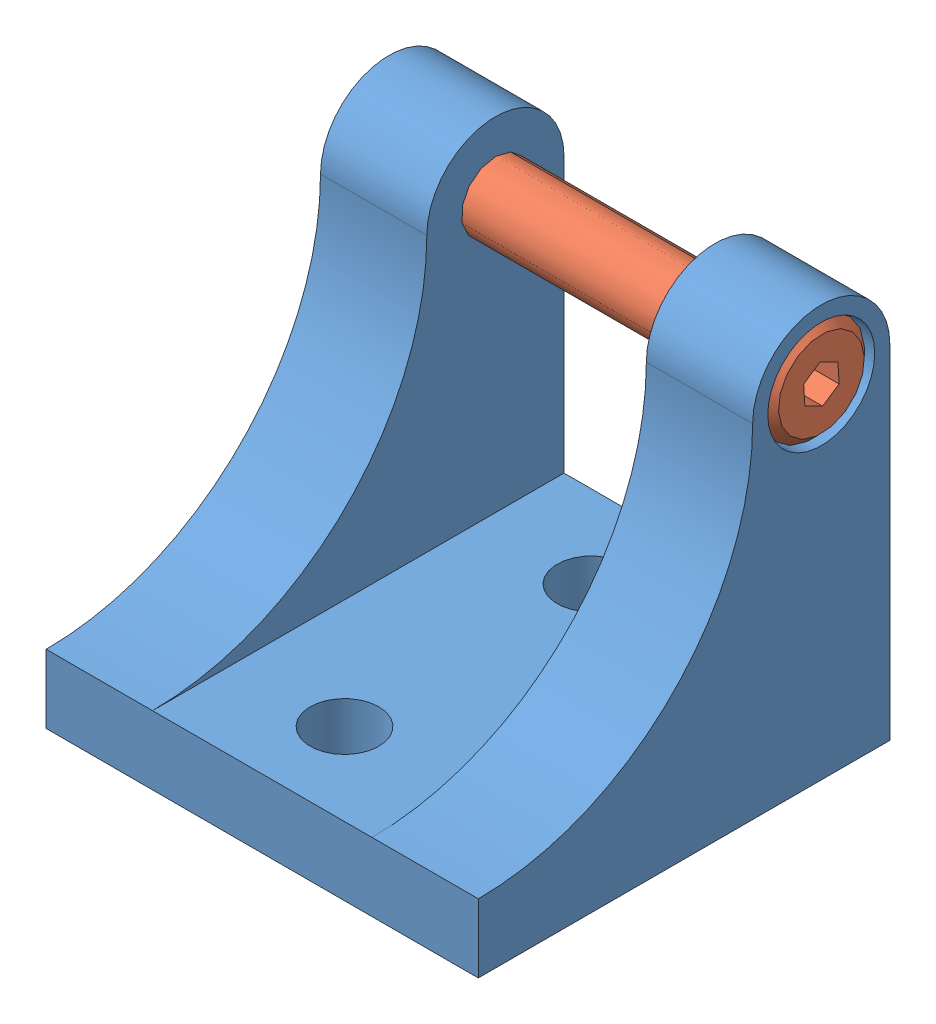
SolidWorks assembly Celvis w-bolt, configuration Default. Lengths in mm.
Overall size (40.02 38.14 38.14).
2 component instances, 2 part files, 2 mates.
Components (placement in the parent):
- HDA Clevis Mount-1: HDA Clevis Mount [Default] at origin size (40 38.1 38.1)
- socket head shoulder screw2_ai-1: socket head shoulder screw2_ai [SHSSCREW 0.25x1-N] at (40.0177 31.75 -31.75) x (-1 0 0) z (0 0.894783 -0.446501) size (39.7 9.53 9.53)
Mates (geometry in assembly coordinates):
- Concentric11: concentric aligned: cylinder of HDA Clevis Mount-1 through (21.1822 31.75 -31.75) axis (1 0 0) radius 3.175; cylinder of socket head shoulder screw2_ai-1 through (46.3677 31.75 -31.75) axis (1 0 0) radius 3.1496
- Coincident2: coincident anti-aligned: plane of HDA Clevis Mount-1 through (9.8425 6.35 0) normal (1 0 0); plane of socket head shoulder screw2_ai-1 through (9.8425 33.1563 -28.9318) normal (-1 0 0)
